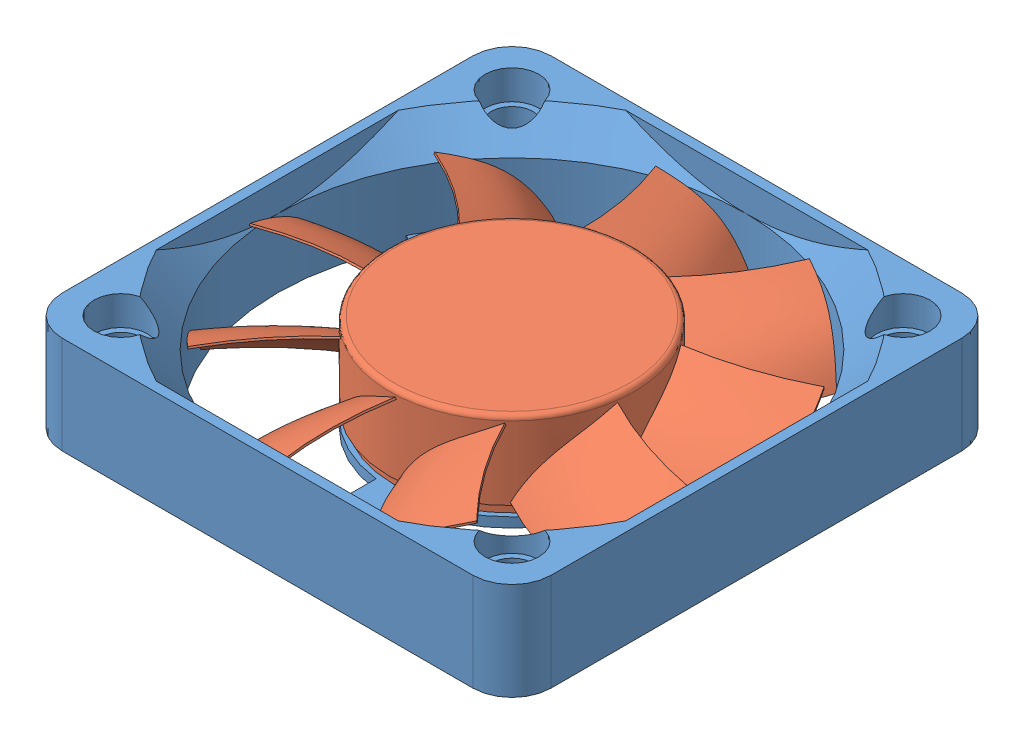
SolidWorks assembly Fan, configuration Default. Lengths in mm.
Overall size (52.09 11.44 52.21).
2 component instances, 2 part files, 2 mates.
Components (placement in the parent):
- Fan base-1: Fan base [Default] at origin size (50 11.44 50)
- Fan blade-1: Fan blade [Default] at (0 2 0) x (0.09341 0 -0.995628) z (0.995628 0 0.09341) size (47.96 9 47.82)
Mates (geometry in assembly coordinates):
- Concentric1: concentric: cylinder of Fan base-1 through (0 1 0) axis (0 -1 0) radius 12.5; cylinder of Fan blade-1 through (0 22.656 0) axis (0 -1 0) radius 12.5
- Coincident1: coincident: plane of Fan base-1 through (0 1 0) normal (0 1 0); plane of Fan blade-1 through (0 1 0) normal (0 -1 0)
